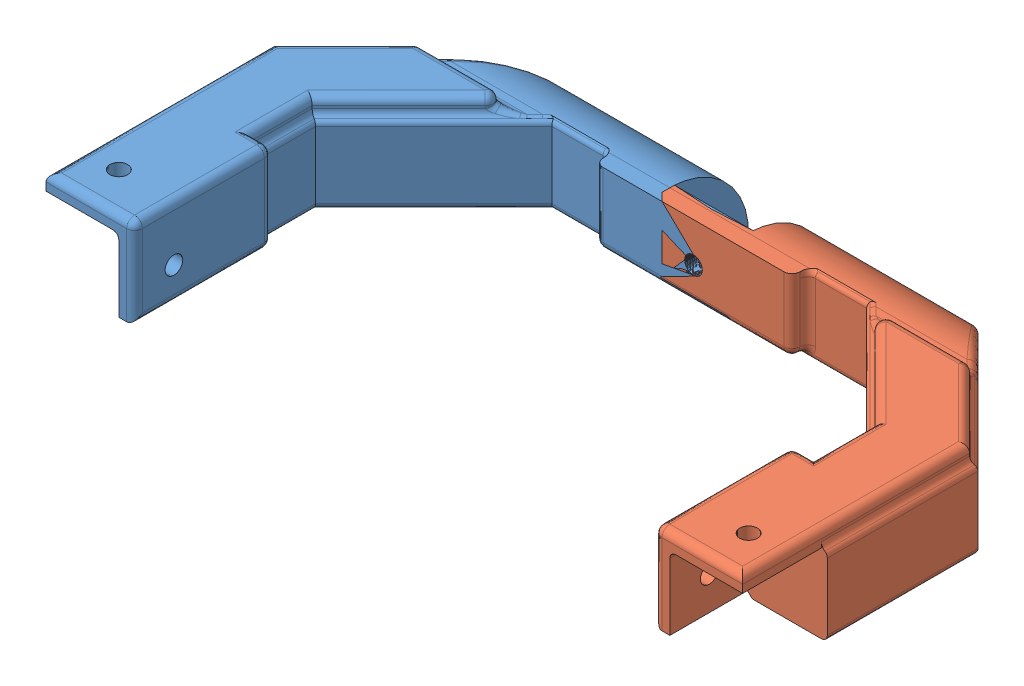
SolidWorks assembly MIRROR, configuration Default. Lengths in mm.
Overall size (180 24 99.99).
2 component instances, 2 part files, 0 mates.
Components (placement in the parent):
- DoorBarCouplerR1-1: DoorBarCouplerR1 [Default] at (-9.8372 58.9985 70.6361) size (100 24 99.99)
- MirrorDoorBarCouplerR1-2: MirrorDoorBarCouplerR1 [Default] at (170.1628 58.9985 70.6361) x (-1 0 0) z (0 0 -1) size (100 24 99.99)
